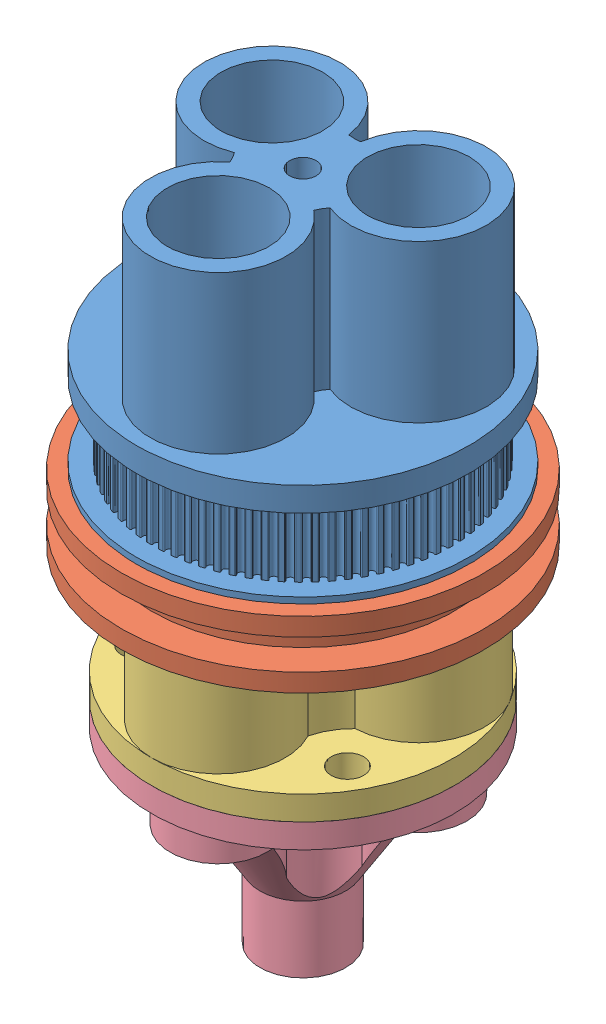
SolidWorks assembly syringe barrel assembly, configuration Default. Lengths in mm.
Overall size (68.27 112.01 68.27).
4 component instances, 4 part files, 9 mates.
Components (placement in the parent):
- barrel mid 1-1: barrel mid 1 [Default] at origin size (55 48.5 55)
- aluminium ring-1: aluminium ring [Default] at (0 -5.5 0) size (60 11 60)
- barrel bottom 1-1: barrel bottom 1 [Default] at (0 -33 0) x (0.999998 0 -0.001745) z (0.001745 0 0.999998) size (55 27.4 55)
- mixing chamber 1-1: mixing chamber 1 [Default] at (0 -68 0) x (-0.866897 0 -0.498488) z (0 1 0) size (50 50 36.01)
Mates (geometry in assembly coordinates):
- Coincident1: coincident: plane of barrel mid 1-1 through (0 0 0) normal (0 -1 0); plane of aluminium ring-1 through (-30 0 0) normal (0 1 0)
- Concentric1: concentric: cylinder of barrel mid 1-1 through (0 -5.5 0) axis (0 1 0) radius 22.5; cylinder of aluminium ring-1 through (0 -11.001 0) axis (0 1 0) radius 22.8
- Coincident4: coincident: plane of barrel bottom 1-1 through (0 -5.6 0) normal (0.207912 0 -0.978148); plane of aluminium ring-1 through (0 -11.001 0) normal (-0.207912 0 0.978148)
- Coincident6: coincident: plane of aluminium ring-1 through (-30 -11 0) normal (0 -1 0); plane of barrel bottom 1-1 through (0 -11 0) normal (0 1 0)
- Concentric2: concentric: cylinder of aluminium ring-1 through (0 -11.001 0) axis (0 1 0) radius 22.8; cylinder of barrel bottom 1-1 through (0 -5.6 0) axis (0 -1 0) radius 22.5
- Coincident7: coincident: plane of aluminium ring-1 through (0 -11.001 0) normal (0.951057 0 -0.309017); plane of barrel bottom 1-1 through (0 -5.6 0) normal (-0.951057 0 0.309017)
- Coincident8: coincident: plane of barrel bottom 1-1 through (0 -33 0) normal (0 -1 0); plane of mixing chamber 1-1 through (0 -33 0) normal (0 1 0)
- Concentric3: concentric: cylinder of barrel bottom 1-1 through (-12.1366 -11 -6.9788) axis (0 -1 0) radius 8.425; cylinder of mixing chamber 1-1 through (-12.1366 -32 -6.9788) axis (0 -1 0) radius 5.25
- Concentric4: concentric: cylinder of barrel bottom 1-1 through (12.1121 -11 -7.0212) axis (0 -1 0) radius 8.425; cylinder of mixing chamber 1-1 through (12.1121 -29 -7.0212) axis (0 -1 0) radius 5.25
